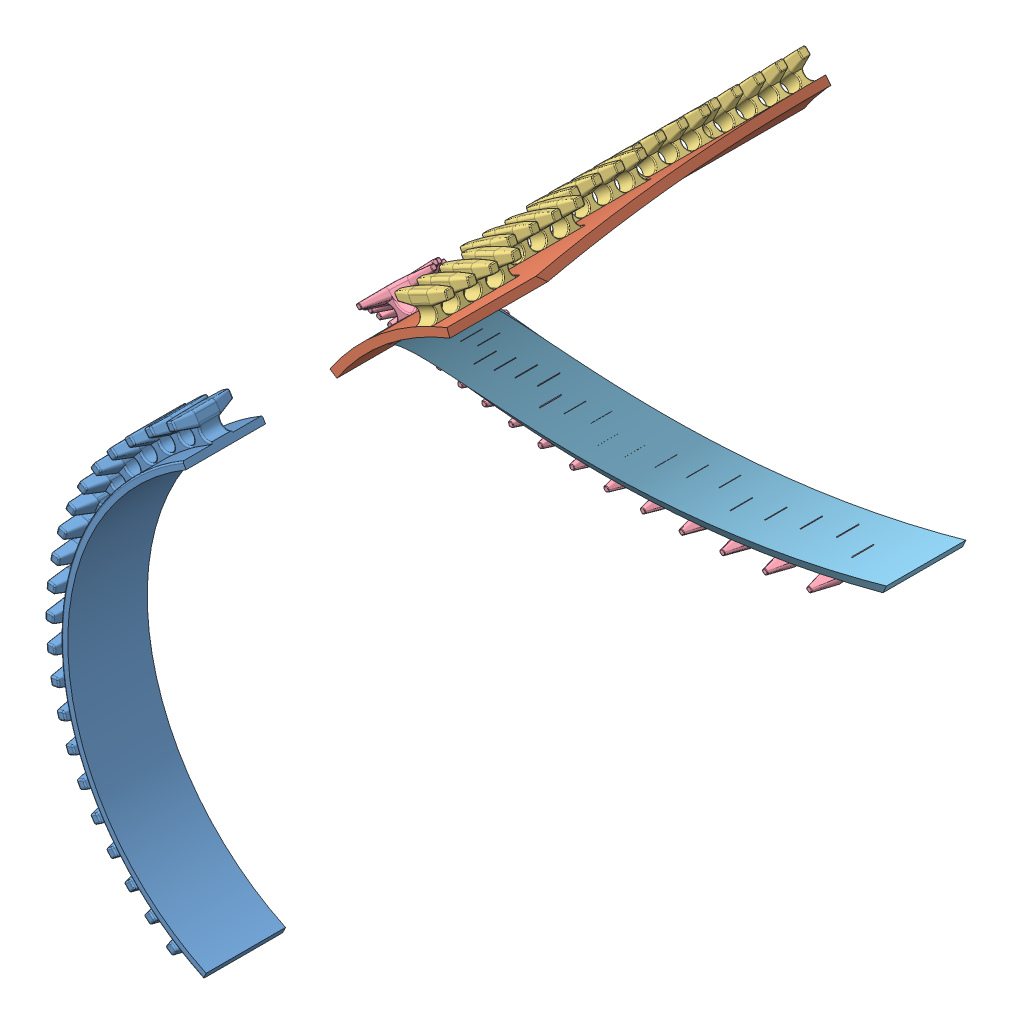
SolidWorks assembly cSL cleats, configuration Default. Lengths in mm.
Overall size (149.11 159.41 238.09).
32 component instances, 9 part files, 87 mates.
Components (placement in the parent):
- cSL axis cleat-1: cSL axis cleat [Default] at (0 0 -332.5) x (-0.834092 0.551626 0) z (0 0 1) size (97.74 122.53 25)
- cSL peel off cleats-1: cSL peel off cleats [Default] at origin size (37.74 31.12 147)
- cSL cross cleat-1: cSL cross cleat [4 cleats] at (-57.3088 53.7928 -479.5) x (0.684387 0.729119 0) z (0 0 1) size (18.07 10.06 28.32)
- cSL cross cleat-2: cSL cross cleat [5 cleats] at (-60.5734 50.0882 -507.5) x (0.637254 0.770653 0) z (0 0 1) size (18.07 10.06 35.32)
- cSL cross cleat-3: cSL cross cleat [4 cleats] at (-50.5364 60.2 -451.5) x (0.765903 0.642956 0) z (0 0 1) size (18.07 10.06 28.32)
- cSL cross cleat-4: cSL cross cleat [4 cleats] at (-43.3967 65.5339 -423.5) x (0.833764 0.55212 0) z (0 0 1) size (18.07 10.06 28.32)
- cSL cross cleat-5: cSL cross cleat [4 cleats] at (-36.1871 69.7743 -395.5) x (0.887714 0.460395 0) z (0 0 1) size (18.07 10.06 28.32)
- cSL cyclinder-1: cSL cyclinder [Default] at origin size (157.2 157.2 10) (hidden)
- cSL diagonal cleat-1: cSL diagonal cleat [Default] at (-50.7271 56.5929 -404.7743) x (0.744644 0.667462 0) z (0 0 1) size (15.95 11.43 15.96)
- cSL diagonal cleat-2: cSL diagonal cleat [Default] at (-50.9 -56.4374 -523.7743) x (-0.742598 0.669737 0) z (0 0 1) size (15.95 11.43 15.96)
- cSL diagonal cleat-3: cSL diagonal cleat [Default] at (-56.2108 -51.1503 -516.7743) x (-0.67303 0.739615 0) z (0 0 1) size (15.95 11.43 15.96)
- cSL diagonal cleat-4: cSL diagonal cleat [Default] at (-60.975 -45.3658 -509.7743) x (-0.596918 0.802302 0) z (0 0 1) size (15.95 11.43 15.96)
- cSL diagonal cleat-5: cSL diagonal cleat [Default] at (-65.1464 -39.1402 -502.7743) x (-0.515002 0.857189 0) z (0 0 1) size (15.95 11.43 15.96)
- cSL diagonal cleat-6: cSL diagonal cleat [Default] at (-75.1523 11.3194 -453.7743) x (0.148939 0.988846 0) z (0 0 1) size (15.95 11.43 15.96)
- cSL diagonal cleat-7: cSL diagonal cleat [Default] at (-73.729 -18.4401 -481.7743) x (-0.242633 0.970118 0) z (0 0 1) size (15.95 11.43 15.96)
- cSL diagonal cleat-8: cSL diagonal cleat [Default] at (-71.5545 -25.6116 -488.7743) x (-0.336995 0.941507 0) z (0 0 1) size (15.95 11.43 15.96)
- cSL diagonal cleat-9: cSL diagonal cleat [Default] at (-75.1866 -11.0894 -474.7743) x (-0.145913 0.989297 0) z (0 0 1) size (15.95 11.43 15.96)
- cSL diagonal cleat-10: cSL diagonal cleat [Default] at (-75.9132 -3.6308 -467.7743) x (-0.047774 0.998858 0) z (0 0 1) size (15.95 11.43 15.96)
- cSL diagonal cleat-11: cSL diagonal cleat [Default] at (-75.9018 3.8631 -460.7743) x (0.05083 0.998707 0) z (0 0 1) size (15.95 11.43 15.96)
- cSL diagonal cleat-12: cSL diagonal cleat [Default] at (-68.6843 -32.534 -495.7743) x (-0.428079 0.903741 0) z (0 0 1) size (15.95 11.43 15.96)
- cSL diagonal cleat-13: cSL diagonal cleat [Default] at (-73.6722 18.6656 -446.7743) x (0.2456 0.969371 0) z (0 0 1) size (15.95 11.43 15.96)
- cSL diagonal cleat-14: cSL diagonal cleat [Default] at (-71.4758 25.8304 -439.7743) x (0.339874 0.940471 0) z (0 0 1) size (15.95 11.43 15.96)
- cSL diagonal cleat-15: cSL diagonal cleat [Default] at (-68.5845 32.744 -432.7743) x (0.430843 0.902427 0) z (0 0 1) size (15.95 11.43 15.96)
- cSL diagonal cleat-16: cSL diagonal cleat [Default] at (-65.0263 39.3393 -425.7743) x (0.517622 0.855609 0) z (0 0 1) size (15.95 11.43 15.96)
- cSL diagonal cleat-17: cSL diagonal cleat [Default] at (-60.8359 45.5521 -418.7743) x (0.59937 0.800472 0) z (0 0 1) size (15.95 11.43 15.96)
- cSL diagonal cleat-18: cSL diagonal cleat [Default] at (-56.054 51.322 -411.7743) x (0.67529 0.737553 0) z (0 0 1) size (15.95 11.43 15.96)
- cSL diagonal helix base-1: cSL diagonal helix base [Default] at (0 0 7) x (0.744644 0.667462 0) z (0 0 1) size (78.61 110.19 165.82)
- cSL cleat glue tab-1: cSL cleat glue tab [Default] x (-0.891007 0.45399 0) z (0 0 1) (suppressed, hidden)
- cSL cleat glue tab horz-1: cSL cleat glue tab horz [Default] at (0 0 -513) x (-1 0 0) z (0 0 1) (suppressed, hidden)
- cSL cleat glue tab horz-2: cSL cleat glue tab horz [Default] at (0 0 -360) x (-1 0 0) z (0 0 1) (suppressed, hidden)
- cSL diagonal cleat-19: cSL diagonal cleat [Default] at (-45.0944 -61.1759 -530.7743) x (-0.804946 0.593348 0) z (0 0 1) size (15.95 11.43 15.96)
- cSL cleats fixtured^cSL cleats-1: cSL cleats fixtured^cSL cleats [Default] at (0 0 -345) x (0.834092 -0.551626 0) z (0 0 -1) (suppressed, hidden, virtual)
Mates (geometry in assembly coordinates):
- Distance1: distance = 332.5 mm aligned: plane of cSL axis cleat-1 through (0 0 -332.5) normal (0 0 1); plane of assembly through (0 0 0) normal (0 0 1)
- Angle1: planar angle = 0.584312 rad anti-aligned: plane of cSL axis cleat-1; plane of assembly through (0 0 0) normal (1 0 0)
- Concentric8: concentric anti-aligned: cylinder of cSL peel off cleats-1 through (0 0 -539) axis (0 0 1) radius 76; cylinder of cSL cross cleat-2 through (0 0 -535.5) axis (0 0 -1) radius 76.6
- Coincident1: coincident anti-aligned: circle of cSL cross cleat-5; plane of cSL peel off cleats-1 through (0 0 -392) normal (0 0 1)
- Concentric12: concentric anti-aligned: cylinder of cSL peel off cleats-1 through (0 0 -539) axis (0 0 1) radius 76; cylinder of cSL cross cleat-5 through (0 0 -402.5) axis (0 0 -1) radius 76.6
- Concentric13: concentric anti-aligned: cylinder of cSL peel off cleats-1 through (0 0 -539) axis (0 0 1) radius 76; cylinder of cSL cross cleat-3 through (0 0 -458.5) axis (0 0 -1) radius 76.6
- Concentric14: concentric anti-aligned: cylinder of cSL peel off cleats-1 through (0 0 -539) axis (0 0 1) radius 76; cylinder of cSL cross cleat-4 through (0 0 -430.5) axis (0 0 -1) radius 76.6
- Concentric15: concentric anti-aligned: cylinder of cSL peel off cleats-1 through (0 0 -539) axis (0 0 1) radius 76; cylinder of cSL cross cleat-1 through (0 0 -486.5) axis (0 0 -1) radius 76.6
- Concentric16: concentric anti-aligned: cylinder of cSL peel off cleats-1 through (0 0 -539) axis (0 0 1) radius 78.6; cylinder of cSL cross cleat-2 through (0 0 -521.5) axis (0 0 -1) radius 76.6
- Coincident12: coincident anti-aligned: plane of cSL cross cleat-1 through (-57.8108 50.2541 -476) normal (0 0 1); plane of cSL cross cleat-3 through (-51.4538 56.7456 -476) normal (0 0 -1)
- Coincident13: coincident anti-aligned: plane of cSL cross cleat-1 through (-57.8108 50.2541 -504) normal (0 0 -1); plane of cSL cross cleat-2 through (-60.8522 46.525 -504) normal (0 0 1)
- Coincident11: coincident anti-aligned: plane of cSL cross cleat-3 through (-51.4538 56.7456 -448) normal (0 0 1); plane of cSL cross cleat-4 through (-44.6993 62.2056 -448) normal (0 0 -1)
- Coincident10: coincident anti-aligned: plane of cSL cross cleat-4 through (-44.6993 62.2056 -420) normal (0 0 1); plane of cSL cross cleat-5 through (-37.8359 66.6033 -420) normal (0 0 -1)
- Concentric17: concentric anti-aligned: cylinder of cSL axis cleat-1 through (0 0 -329.2) axis (0 0 -1) radius 76; cylinder of cSL peel off cleats-1 through (0 0 -539) axis (0 0 1) radius 76
- Concentric1: concentric anti-aligned: cylinder of cSL cyclinder-1 through (0 0 10) axis (0 0 -1) radius 76; cylinder of cSL diagonal cleat-1 through (0 0 -411.7743) axis (0 0 1) radius 76
- Concentric5: concentric anti-aligned: cylinder of cSL cyclinder-1 through (0 0 10) axis (0 0 -1) radius 76; cylinder of cSL diagonal cleat-2 through (0 0 -530.7743) axis (0 0 1) radius 76
- Concentric6: concentric anti-aligned: cylinder of cSL cyclinder-1 through (0 0 10) axis (0 0 -1) radius 76; cylinder of cSL diagonal cleat-3 through (0 0 -523.7743) axis (0 0 1) radius 76
- Concentric7: concentric anti-aligned: cylinder of cSL cyclinder-1 through (0 0 10) axis (0 0 -1) radius 76; cylinder of cSL diagonal cleat-4 through (0 0 -516.7743) axis (0 0 1) radius 76
- Concentric18: concentric anti-aligned: cylinder of cSL cyclinder-1 through (0 0 10) axis (0 0 -1) radius 76; cylinder of cSL diagonal cleat-5 through (0 0 -509.7743) axis (0 0 1) radius 76
- Concentric9: concentric anti-aligned: cylinder of cSL cyclinder-1 through (0 0 10) axis (0 0 -1) radius 76; cylinder of cSL diagonal cleat-6 through (0 0 -460.7743) axis (0 0 1) radius 76
- Concentric10: concentric anti-aligned: cylinder of cSL cyclinder-1 through (0 0 10) axis (0 0 -1) radius 76; cylinder of cSL diagonal cleat-7 through (0 0 -488.7743) axis (0 0 1) radius 76
- Concentric11: concentric anti-aligned: cylinder of cSL cyclinder-1 through (0 0 10) axis (0 0 -1) radius 76; cylinder of cSL diagonal cleat-8 through (0 0 -495.7743) axis (0 0 1) radius 76
- Concentric19: concentric anti-aligned: cylinder of cSL cyclinder-1 through (0 0 10) axis (0 0 -1) radius 76; cylinder of cSL diagonal cleat-9 through (0 0 -481.7743) axis (0 0 1) radius 76
- Concentric20: concentric anti-aligned: cylinder of cSL cyclinder-1 through (0 0 10) axis (0 0 -1) radius 76; cylinder of cSL diagonal cleat-10 through (0 0 -474.7743) axis (0 0 1) radius 76
- Concentric21: concentric anti-aligned: cylinder of cSL cyclinder-1 through (0 0 10) axis (0 0 -1) radius 76; cylinder of cSL diagonal cleat-11 through (0 0 -467.7743) axis (0 0 1) radius 76
- Concentric22: concentric anti-aligned: cylinder of cSL cyclinder-1 through (0 0 10) axis (0 0 -1) radius 76; cylinder of cSL diagonal cleat-12 through (0 0 -502.7743) axis (0 0 1) radius 76
- Concentric23: concentric anti-aligned: cylinder of cSL cyclinder-1 through (0 0 10) axis (0 0 -1) radius 76; cylinder of cSL diagonal cleat-13 through (0 0 -453.7743) axis (0 0 1) radius 76
- Concentric24: concentric anti-aligned: cylinder of cSL cyclinder-1 through (0 0 10) axis (0 0 -1) radius 76; cylinder of cSL diagonal cleat-14 through (0 0 -446.7743) axis (0 0 1) radius 76
- Concentric25: concentric anti-aligned: cylinder of cSL cyclinder-1 through (0 0 10) axis (0 0 -1) radius 76; cylinder of cSL diagonal cleat-16 through (0 0 -432.7743) axis (0 0 1) radius 76
- Concentric26: concentric anti-aligned: cylinder of cSL cyclinder-1 through (0 0 10) axis (0 0 -1) radius 76; cylinder of cSL diagonal cleat-15 through (0 0 -439.7743) axis (0 0 1) radius 76
- Concentric27: concentric anti-aligned: cylinder of cSL cyclinder-1 through (0 0 10) axis (0 0 -1) radius 76; cylinder of cSL diagonal cleat-17 through (0 0 -425.7743) axis (0 0 1) radius 76
- Concentric28: concentric anti-aligned: cylinder of cSL cyclinder-1 through (0 0 10) axis (0 0 -1) radius 76; cylinder of cSL diagonal cleat-18 through (0 0 -418.7743) axis (0 0 1) radius 76
- Coincident2: coincident anti-aligned: plane of cSL diagonal cleat-1 through (0 0 -411.7743) normal (0 0 -1); plane of cSL diagonal cleat-18 through (0 0 -411.7743) normal (0 0 1)
- Coincident3: coincident anti-aligned: plane of cSL diagonal cleat-1 through (-57.9716 53.0778 -411.7743) normal (-0.67529 -0.737553 0); plane of cSL diagonal cleat-18 through (-57.9716 53.0778 -418.7743) normal (0.67529 0.737553 0)
- Coincident47: coincident aligned: plane of cSL diagonal cleat-1 through (-50.7271 56.5929 -404.7743) normal (0 0 1); plane of cSL diagonal helix base-1 through (0 0 -404.7743) normal (0 0 1)
- Coincident48: coincident aligned: plane of cSL diagonal cleat-1 through (-52.4625 58.529 -411.7743) normal (0.744644 0.667462 0); plane of cSL diagonal helix base-1 through (-51.5948 57.561 -417.2743) normal (0.744644 0.667462 0)
- Coincident37: coincident anti-aligned: plane of cSL diagonal cleat-2 through (-52.6414 -58.3682 -530.7743) normal (-0.742598 0.669737 0); plane of cSL diagonal cleat-3 through (-52.6414 -58.3682 -523.7743) normal (0.742598 -0.669737 0)
- Coincident38: coincident anti-aligned: plane of cSL diagonal cleat-2 through (0 0 -523.7743) normal (0 0 1); plane of cSL diagonal cleat-3 through (0 0 -523.7743) normal (0 0 -1)
- Coincident35: coincident anti-aligned: plane of cSL diagonal cleat-3 through (-58.1338 -52.9001 -523.7743) normal (-0.67303 0.739615 0); plane of cSL diagonal cleat-4 through (-58.1338 -52.9001 -516.7743) normal (0.67303 -0.739615 0)
- Coincident36: coincident anti-aligned: plane of cSL diagonal cleat-3 through (0 0 -516.7743) normal (0 0 1); plane of cSL diagonal cleat-4 through (0 0 -516.7743) normal (0 0 -1)
- Coincident33: coincident anti-aligned: plane of cSL diagonal cleat-4 through (-63.061 -46.9177 -516.7743) normal (-0.596918 0.802302 0); plane of cSL diagonal cleat-5 through (-63.061 -46.9177 -509.7743) normal (0.596918 -0.802302 0)
- Coincident34: coincident anti-aligned: plane of cSL diagonal cleat-4 through (0 0 -509.7743) normal (0 0 1); plane of cSL diagonal cleat-5 through (0 0 -509.7743) normal (0 0 -1)
- Coincident31: coincident anti-aligned: plane of cSL diagonal cleat-5 through (-67.375 -40.4792 -509.7743) normal (-0.515002 0.857189 0); plane of cSL diagonal cleat-12 through (-67.375 -40.4792 -502.7743) normal (0.515002 -0.857189 0)
- Coincident32: coincident anti-aligned: plane of cSL diagonal cleat-5 through (0 0 -502.7743) normal (0 0 1); plane of cSL diagonal cleat-12 through (0 0 -502.7743) normal (0 0 -1)
- Coincident17: coincident anti-aligned: plane of cSL diagonal cleat-6 through (-77.7233 11.7066 -460.7743) normal (0.148939 0.988846 0); plane of cSL diagonal cleat-13 through (-77.7233 11.7066 -453.7743) normal (-0.148939 -0.988846 0)
- Coincident18: coincident anti-aligned: plane of cSL diagonal cleat-6 through (0 0 -453.7743) normal (0 0 1); plane of cSL diagonal cleat-13 through (0 0 -453.7743) normal (0 0 -1)
- Coincident19: coincident anti-aligned: plane of cSL diagonal cleat-6 through (-78.4984 3.9952 -460.7743) normal (-0.05083 -0.998707 0); plane of cSL diagonal cleat-11 through (-78.4984 3.9952 -467.7743) normal (0.05083 0.998707 0)
- Coincident20: coincident anti-aligned: plane of cSL diagonal cleat-6 through (0 0 -460.7743) normal (0 0 -1); plane of cSL diagonal cleat-11 through (0 0 -460.7743) normal (0 0 1)
- Coincident25: coincident anti-aligned: plane of cSL diagonal cleat-7 through (-76.2513 -19.071 -488.7743) normal (-0.242633 0.970118 0); plane of cSL diagonal cleat-9 through (-76.2513 -19.071 -481.7743) normal (0.242633 -0.970118 0)
- Coincident26: coincident anti-aligned: plane of cSL diagonal cleat-7 through (0 0 -481.7743) normal (0 0 1); plane of cSL diagonal cleat-9 through (0 0 -481.7743) normal (0 0 -1)
- Coincident27: coincident anti-aligned: plane of cSL diagonal cleat-7 through (-74.0024 -26.4878 -488.7743) normal (0.336995 -0.941507 0); plane of cSL diagonal cleat-8 through (-74.0024 -26.4878 -495.7743) normal (-0.336995 0.941507 0)
- Coincident28: coincident anti-aligned: plane of cSL diagonal cleat-7 through (0 0 -488.7743) normal (0 0 -1); plane of cSL diagonal cleat-8 through (0 0 -488.7743) normal (0 0 1)
- Coincident29: coincident anti-aligned: plane of cSL diagonal cleat-8 through (-71.0341 -33.647 -495.7743) normal (0.428079 -0.903741 0); plane of cSL diagonal cleat-12 through (-71.0341 -33.647 -502.7743) normal (-0.428079 0.903741 0)
- Coincident30: coincident anti-aligned: plane of cSL diagonal cleat-8 through (0 0 -495.7743) normal (0 0 -1); plane of cSL diagonal cleat-12 through (0 0 -495.7743) normal (0 0 1)
- Coincident23: coincident anti-aligned: plane of cSL diagonal cleat-9 through (-77.7588 -11.4688 -481.7743) normal (-0.145913 0.989297 0); plane of cSL diagonal cleat-10 through (-77.7588 -11.4688 -474.7743) normal (0.145913 -0.989297 0)
- Coincident24: coincident anti-aligned: plane of cSL diagonal cleat-9 through (0 0 -474.7743) normal (0 0 1); plane of cSL diagonal cleat-10 through (0 0 -474.7743) normal (0 0 -1)
- Coincident21: coincident anti-aligned: plane of cSL diagonal cleat-10 through (-78.5103 -3.755 -474.7743) normal (-0.047774 0.998858 0); plane of cSL diagonal cleat-11 through (-78.5103 -3.755 -467.7743) normal (0.047774 -0.998858 0)
- Coincident22: coincident anti-aligned: plane of cSL diagonal cleat-10 through (0 0 -467.7743) normal (0 0 1); plane of cSL diagonal cleat-11 through (0 0 -467.7743) normal (0 0 -1)
- Coincident15: coincident anti-aligned: plane of cSL diagonal cleat-13 through (-76.1926 19.3042 -453.7743) normal (0.2456 0.969371 0); plane of cSL diagonal cleat-14 through (-76.1926 19.3042 -446.7743) normal (-0.2456 -0.969371 0)
- Coincident16: coincident anti-aligned: plane of cSL diagonal cleat-13 through (0 0 -446.7743) normal (0 0 1); plane of cSL diagonal cleat-14 through (0 0 -446.7743) normal (0 0 -1)
- Coincident49: coincident anti-aligned: plane of cSL diagonal cleat-14 through (-73.921 26.7141 -446.7743) normal (0.339874 0.940471 0); plane of cSL diagonal cleat-15 through (-73.921 26.7141 -439.7743) normal (-0.339874 -0.940471 0)
- Coincident14: coincident anti-aligned: plane of cSL diagonal cleat-14 through (0 0 -439.7743) normal (0 0 1); plane of cSL diagonal cleat-15 through (0 0 -439.7743) normal (0 0 -1)
- Coincident50: coincident anti-aligned: plane of cSL diagonal cleat-15 through (-70.9308 33.8642 -439.7743) normal (0.430843 0.902427 0); plane of cSL diagonal cleat-16 through (-70.9308 33.8642 -432.7743) normal (-0.430843 -0.902427 0)
- Coincident51: coincident anti-aligned: plane of cSL diagonal cleat-15 through (0 0 -432.7743) normal (0 0 1); plane of cSL diagonal cleat-16 through (0 0 -432.7743) normal (0 0 -1)
- Coincident9: coincident anti-aligned: plane of cSL diagonal cleat-16 through (-67.2509 40.6851 -432.7743) normal (0.517622 0.855609 0); plane of cSL diagonal cleat-17 through (-67.2509 40.6851 -425.7743) normal (-0.517622 -0.855609 0)
- Coincident52: coincident anti-aligned: plane of cSL diagonal cleat-16 through (0 0 -425.7743) normal (0 0 1); plane of cSL diagonal cleat-17 through (0 0 -425.7743) normal (0 0 -1)
- Coincident4: coincident anti-aligned: plane of cSL diagonal cleat-17 through (-62.9171 47.1105 -425.7743) normal (0.59937 0.800472 0); plane of cSL diagonal cleat-18 through (-62.9171 47.1105 -418.7743) normal (-0.59937 -0.800472 0)
- Coincident6: coincident anti-aligned: plane of cSL diagonal cleat-17 through (-62.9171 47.1105 -425.7743) normal (0.59937 0.800472 0); plane of cSL diagonal cleat-18 through (-62.9171 47.1105 -418.7743) normal (-0.59937 -0.800472 0)
- Coincident7: coincident anti-aligned: plane of cSL diagonal cleat-17 through (0 0 -418.7743) normal (0 0 1); plane of cSL diagonal cleat-18 through (0 0 -418.7743) normal (0 0 -1)
- Concentric29: concentric anti-aligned: cylinder of cSL axis cleat-1 through (0 0 -320) axis (0 0 -1) radius 78.1; cylinder of cSL cleat glue tab-1 through (0 0 0) axis (0 0 1) radius 78.6
- Coincident56: coincident aligned: plane of cSL cleat glue tab-1 through (0 0 0) normal (0 0 1); plane of assembly through (0 0 0) normal (0 0 1)
- Parallel1: parallel aligned: plane of cSL cleat glue tab horz-1 through (0 0 -508) normal (0 0 1); plane of assembly through (0 0 0) normal (0 0 1)
- Parallel2: parallel aligned: plane of cSL cleat glue tab horz-2 through (0 0 -355) normal (0 0 1); plane of assembly through (0 0 0) normal (0 0 1)
- Concentric30: concentric anti-aligned: cylinder of cSL cleat glue tab-1 through (0 0 0) axis (0 0 1) radius 83.6; cylinder of cSL cleat glue tab horz-1 through (0 0 -508) axis (0 0 -1) radius 83.6
- Concentric31: concentric anti-aligned: cylinder of cSL cleat glue tab-1 through (0 0 0) axis (0 0 1) radius 83.6; cylinder of cSL cleat glue tab horz-2 through (0 0 -355) axis (0 0 -1) radius 83.6
- Coincident60: coincident aligned: plane of cSL cleat glue tab-1; plane of cSL cleat glue tab horz-2 through (-37.9536 -74.4881 -355) normal (-0.891007 0.45399 0)
- Parallel3: parallel anti-aligned: plane of cSL cleat glue tab horz-2 through (-8 -83.2163 -355) normal (-1 0 0); plane of assembly through (0 0 0) normal (1 0 0)
- Parallel4: parallel anti-aligned: plane of cSL cleat glue tab horz-1 through (-8 -83.2163 -508) normal (-1 0 0); plane of assembly through (0 0 0) normal (1 0 0)
- Distance2: distance = 35 mm aligned: plane of cSL cleat glue tab-1 through (-35.8398 -67.0355 -320) normal (0 0 1); plane of cSL cleat glue tab horz-2 through (0 0 -355) normal (0 0 1)
- Distance3: distance = 188 mm aligned: plane of cSL cleat glue tab horz-1 through (0 0 -508) normal (0 0 1); plane of cSL cleat glue tab-1 through (-35.8398 -67.0355 -320) normal (0 0 1)
- Concentric32: concentric: cylinder of cSL diagonal cleat-2 through (0 0 -530.7743) axis (0 0 1) radius 76; cylinder of cSL diagonal cleat-19 through (0 0 -537.7743) axis (0 0 1) radius 76
- Coincident61: coincident: plane of cSL diagonal cleat-2 through (-46.6371 -63.2688 -530.7743) normal (0.804946 -0.593348 0); plane of cSL diagonal cleat-19 through (-46.6371 -63.2688 -537.7743) normal (-0.804946 0.593348 0)
- Coincident62: coincident anti-aligned: plane of cSL diagonal cleat-2 through (0 0 -530.7743) normal (0 0 -1); plane of cSL diagonal cleat-19 through (0 0 -530.7743) normal (0 0 1)
- InPlace1: in place: plane of cSL axis cleat-1 through (0 0 -345) normal (0 0 -1); plane of ? through (0 0 -345) normal (0 0 -1); moOrthogonalPlaneRef_w of cSL axis cleat-1 through (0 0 -345) normal (0 0 -1); unknown of ?; plane of cSL axis cleat-1 through (0 0 -345) normal (0 0 -1); plane of ? through (0 0 -345) normal (-1 0 0); plane of cSL axis cleat-1 through (0 0 -345) normal (0 0 -1); unknown of cSL cleats fixtured^cSL cleats-1
- Coincident63: coincident aligned: plane of cSL axis cleat-1; plane of cSL cleats fixtured^cSL cleats-1
- Coincident64: coincident aligned: moOrthogonalPlaneRef_w of cSL axis cleat-1 through (0 0 -345) normal (-0.551626 -0.834092 0); plane of cSL cleats fixtured^cSL cleats-1
- Coincident65: coincident anti-aligned: moOrthogonalPlaneRef_w of cSL axis cleat-1 through (0 0 -345) normal (-0.834092 0.551626 0); plane of cSL cleats fixtured^cSL cleats-1
